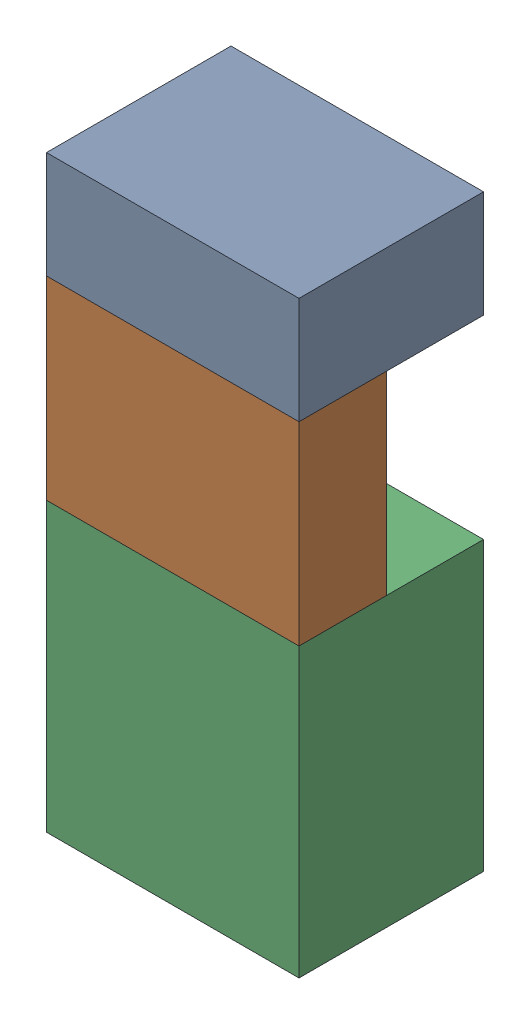
SolidWorks assembly SUP_K4, configuration Default. Lengths in mm.
Overall size (13 30.3 9.5).
6 component instances, 3 part files, 0 mates.
Components (placement in the parent):
- 1151724928-1: 1151724928 [Default] at (52.705 41.975 0) size (13 5.5 9.5)
  - Extruded_2-1: Extruded_2 [Default] at origin size (13 5.5 9.5)
- 1151725064-1: 1151725064 [Default] at (52.705 34.225 5) size (13 10 4.5)
  - Extruded_3-1: Extruded_3 [Default] at origin size (13 10 4.5)
- 1151724792-1: 1151724792 [Default] at (52.705 21.825 0) size (13 14.8 9.5)
  - Extruded_4-1: Extruded_4 [Default] at origin size (13 14.8 9.5)
